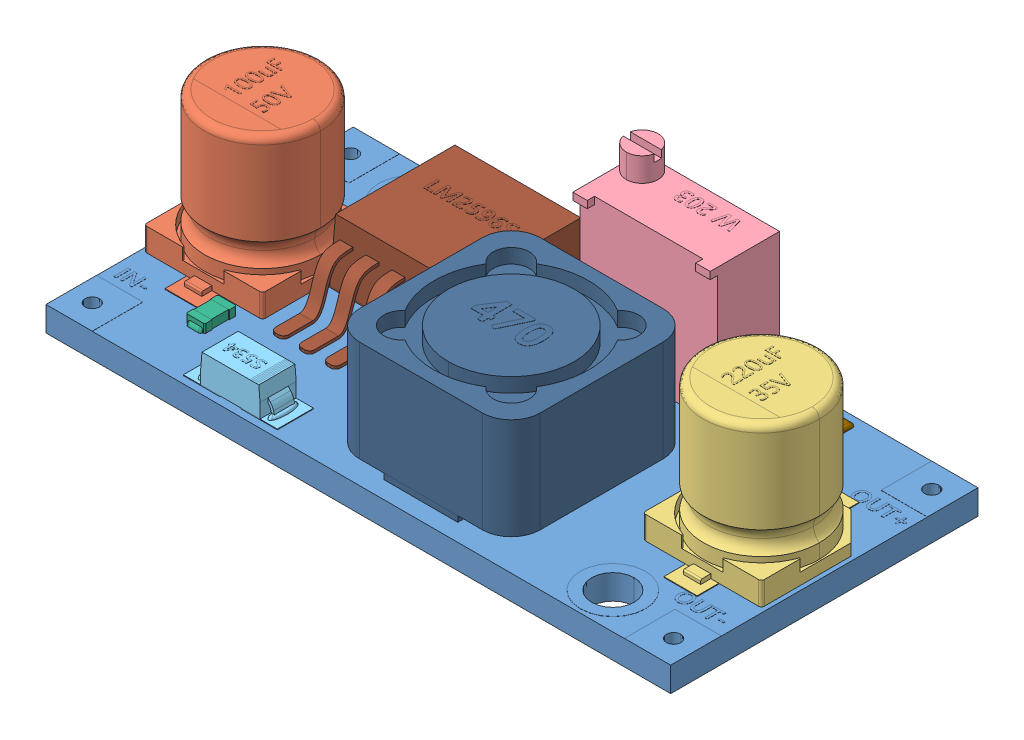
SolidWorks assembly LM2596 DC to DC Buck Converter 3 A.STEP, configuration Default. Lengths in mm.
Overall size (43.2 15.15 21.25).
12 component instances, 11 part files, 0 mates.
Components (placement in the parent):
- lm2596board.STEP-1: lm2596board.STEP [Default] at origin size (43.2 1.71 21.25)
- smd100uF.STEP-1: smd100uF.STEP [Default] at (-17.25 2.55 0) x (0 0 -1) z (1 0 0) size (11.2 9.76 8.2)
- smd220uF.STEP-1: smd220uF.STEP [Default] at (17.25 2.55 0) x (0 0 -1) z (1 0 0) size (11.2 9.76 8.2)
- TrimmerW203.STEP-1: TrimmerW203.STEP [Default] at (4.6271 6.95 -9.1276) size (9.5 15.15 4.81)
- smdS537diode.STEP-1: smdS537diode.STEP [Default] at (-9.35 1.75 8.875) x (-1 0 0) z (0 0 -1) size (6.5 2.06 2.5)
- smdceramiccapacitor.STEP-1: smdceramiccapacitor.STEP [Default] at (-15 1.7 5.7969) x (0 0 1) z (-1 0 0) size (2.52 0.61 1.3)
- smdceramiccapacitor.STEP-2: smdceramiccapacitor.STEP [Default] at (-1.3196 1.7 -5.2916) x (0 0 1) z (-1 0 0) size (2.52 0.61 1.3)
- smdResistor331.STEP-1: smdResistor331.STEP [Default] at (-1.2696 1.7 -8.4665) x (0 0 1) z (-1 0 0) size (2.53 0.63 1.31)
- smdResistor102.STEP-1: smdResistor102.STEP [Default] at (10.7771 1.7 -8.4665) x (0 0 -1) z (1 0 0) size (2.53 0.63 1.31)
- smdLED.STEP-1: smdLED.STEP [Default] at (13.0521 1.75 -8.4701) x (0 0 -1) z (1 0 0) size (3.23 0.86 1.26)
- smbInductor470.STEP-1: smbInductor470.STEP [Default] at (3.1271 2.1 3.175) size (12.5 7.41 12.5)
- LM2596S.STEP-1: LM2596S.STEP [Default] at (-8.0627 1.8 -4.5407) size (9.8 4.61 14.95)
